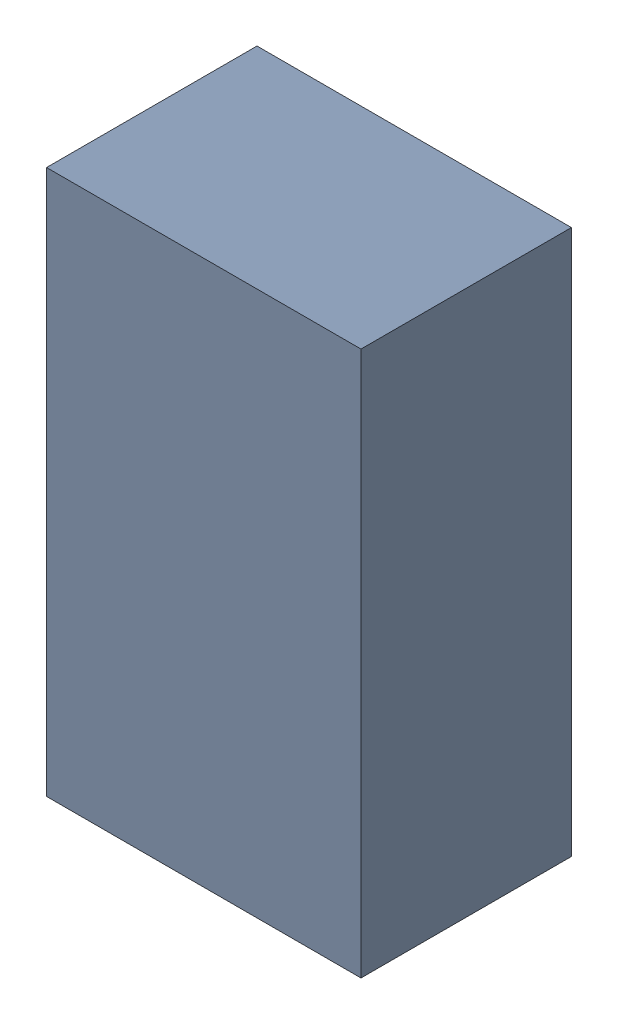
SolidWorks assembly U7Kanaloa_v2.0.0_Motor, configuration Default. Lengths in mm.
Overall size (1.27 2.2 0.85).
2 component instances, 1 part files, 0 mates.
Components (placement in the parent):
- 334788272-1: 334788272 [Default] at (114.322 108.331 -3.7524) size (1.27 2.2 0.85)
  - Extruded_16-1: Extruded_16 [Default] at origin size (1.27 2.2 0.85)
